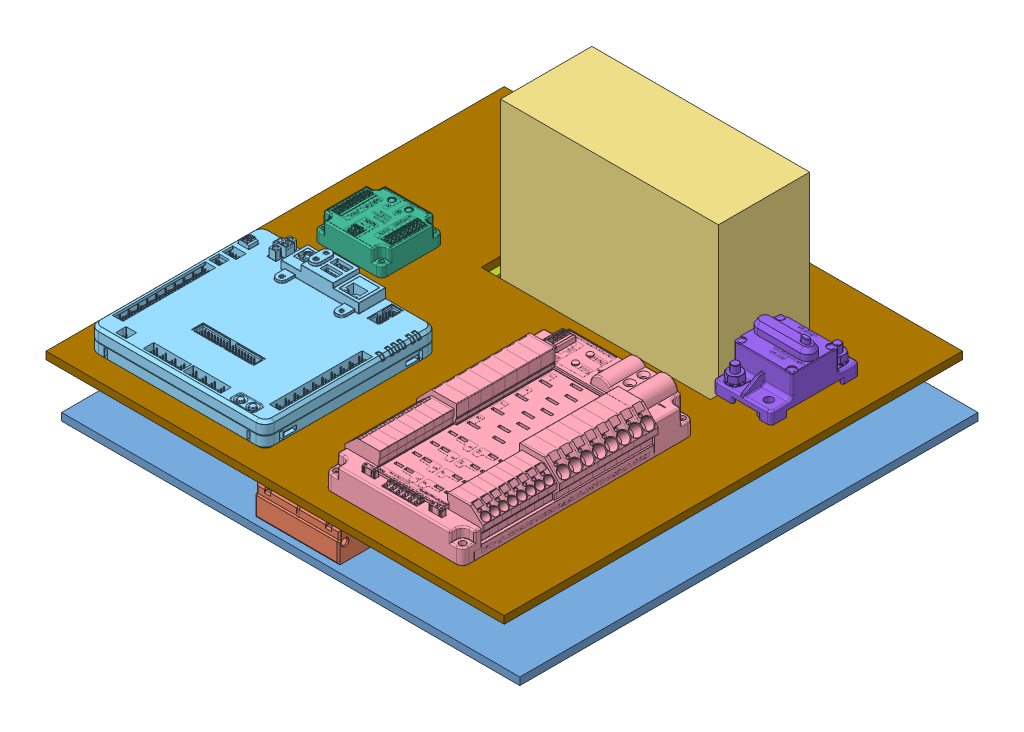
SolidWorks assembly 2board, configuration Default. Lengths in mm.
Overall size (381 173.1 393.95).
14 component instances, 9 part files, 44 mates.
Components (placement in the parent):
- e-board-1: e-board [Default] at (11.1903 208.843 469.4515) size (381 6.22 381)
- Speed Controller-1: Speed Controller [Default] at (218.8091 230.9035 409.6015) x (0 0 -1) z (0 -1 0) size (30.12 70.11 24.39)
- Speed Controller-2: Speed Controller [Default] at (195.4197 230.9035 327.0515) x (0 0 -1) z (0 -1 0) size (30.12 70.11 24.39)
- Speed Controller-3: Speed Controller [Default] at (195.4197 230.9035 288.9515) x (0 0 -1) z (0 -1 0) size (30.12 70.11 24.39)
- Speed Controller-4: Speed Controller [Default] at (195.4197 230.9035 365.1515) x (0 0 -1) z (0 -1 0) size (30.12 70.11 24.39)
- Battery-1: Battery [Default] at (134.8883 215.066 152.2055) x (0 0 1) z (-1 0 0) size (75.95 166.88 181.1)
- PDP-1: PDP [Default] at (283.1225 272.4192 373.3122) x (0 0 1) z (-1 0 0) size (192.68 36.15 120.93)
- Roborio-1: Roborio [Default] at (102.9515 275.391 393.5258) x (1 0 0) z (0 1 0) size (146.27 143.19 36.83)
- VRM-1: VRM [Default] at (71.5666 272.8449 263.7102) size (56.39 19.92 51.56)
- radio b;ock-1: radio b;ock [Default] at (49.2903 215.066 259.9015) size (69.85 25.4 95.25)
- Breaker-1: Breaker [Default] at (342.6603 270.565 198.3394) x (0 0 -1) z (1 0 0) size (73.72 42.2 48.95)
- board with battery cut out-1: board with battery cut out [Default] at (11.1903 259.516 482.4055) size (381 6.22 381)
- Speed Controller-5: Speed Controller [Default] at (201.7697 230.9035 449.4587) x (0 0 -1) z (0 -1 0) size (30.12 70.11 24.39)
- Speed Controller-7: Speed Controller [Default] at (189.0697 230.9035 253.3915) x (0 0 -1) z (0 -1 0) size (30.12 70.11 24.39)
Mates (geometry in assembly coordinates):
- Coincident1: coincident anti-aligned: plane of e-board-1 through (11.1903 215.066 469.4515) normal (0 1 0); plane of Speed Controller-1 through (183.8841 215.066 394.5392) normal (0 -1 0)
- Perpendicular2: perpendicular: plane of e-board-1 through (392.1903 215.066 469.4515) normal (1 0 0); plane of Speed Controller-1 through (231.0297 237.5535 409.3615) normal (0 0 -1)
- Distance1: distance = 57.15 mm: plane of Speed Controller-1 through (231.4297 237.5535 412.3015) normal (0 0 1); line of e-board-1 through (11.1903 208.843 469.4515) axis (1 0 0)
- Distance2: distance = 222.25 mm: line of Speed Controller-1 through (232.2997 237.5535 411.9015) axis (0 0 1); line of e-board-1 through (11.1903 215.066 88.4515) axis (0 0 1)
- Coincident5: coincident anti-aligned: plane of e-board-1 through (11.1903 215.066 469.4515) normal (0 1 0); plane of Speed Controller-4 through (160.4947 215.066 350.0892) normal (0 -1 0)
- Coincident6: coincident anti-aligned: plane of e-board-1 through (11.1903 215.066 469.4515) normal (0 1 0); plane of Speed Controller-3 through (160.4947 215.066 273.8892) normal (0 -1 0)
- Coincident7: coincident anti-aligned: plane of e-board-1 through (11.1903 215.066 469.4515) normal (0 1 0); plane of Speed Controller-2 through (160.4947 215.066 311.9892) normal (0 -1 0)
- Perpendicular3: perpendicular: plane of e-board-1 through (392.1903 215.066 469.4515) normal (1 0 0); plane of Speed Controller-4 through (207.6403 237.5535 364.9115) normal (0 0 -1)
- Perpendicular5: perpendicular: plane of e-board-1 through (392.1903 215.066 469.4515) normal (1 0 0); plane of Speed Controller-3 through (207.6403 237.5535 286.1715) normal (0 0 -1)
- Perpendicular6: perpendicular: plane of e-board-1 through (392.1903 215.066 469.4515) normal (1 0 0); plane of Speed Controller-2 through (207.6403 237.5535 324.2715) normal (0 0 -1)
- Distance3: distance = 184.15 mm: plane of Speed Controller-4 through (208.0403 237.5535 367.4515) normal (1 0 0); line of e-board-1 through (392.1903 215.066 469.4515) axis (0 0 -1)
- Distance5: distance = 184.15 mm aligned: plane of Speed Controller-2 through (208.0403 237.5535 328.0815) normal (1 0 0); plane of e-board-1 through (392.1903 215.066 469.4515) normal (1 0 0)
- Distance6: distance = 101.6 mm aligned: plane of Speed Controller-4 through (209.3103 237.5535 367.8515) normal (0 0 1); plane of e-board-1 through (11.1903 215.066 469.4515) normal (0 0 1)
- Distance7: distance = 139.7 mm aligned: plane of Speed Controller-2 through (208.0403 237.5535 329.7515) normal (0 0 1); plane of e-board-1 through (11.1903 215.066 469.4515) normal (0 0 1)
- Distance8: distance = 184.15 mm: plane of Speed Controller-3 through (208.0403 237.5535 291.2515) normal (1 0 0); line of e-board-1 through (392.1903 215.066 469.4515) axis (0 0 -1)
- Distance9: distance = 177.8 mm aligned: plane of Speed Controller-3 through (208.0403 237.5535 291.6515) normal (0 0 1); plane of e-board-1 through (11.1903 215.066 469.4515) normal (0 0 1)
- Coincident19: coincident anti-aligned: plane of e-board-1 through (11.1903 215.066 469.4515) normal (0 1 0); plane of Battery-1 through (134.8883 215.066 152.2055) normal (0 -1 0)
- Distance11: distance = 76.2 mm aligned: plane of Battery-1 through (315.9903 381.944 152.2055) normal (1 0 0); plane of e-board-1 through (392.1903 215.066 469.4515) normal (1 0 0)
- Coincident39: coincident aligned: plane of e-board-1 through (392.1903 215.066 469.4515) normal (1 0 0); plane of board with battery cut out-1 through (392.1903 272.089 482.4055) normal (1 0 0)
- Distance25: distance = 44.45 mm anti-aligned: plane of e-board-1 through (11.1903 215.066 469.4515) normal (0 1 0); plane of board with battery cut out-1 through (11.1903 259.516 482.4055) normal (0 -1 0)
- Coincident42: coincident anti-aligned: plane of PDP-1 through (225.7185 272.089 465.3364) normal (0 -1 0); plane of board with battery cut out-1 through (11.1903 272.089 482.4055) normal (0 1 0)
- Coincident43: coincident anti-aligned: plane of Breaker-1 through (363.031 272.089 228.8619) normal (0 -1 0); plane of board with battery cut out-1 through (11.1903 272.089 482.4055) normal (0 1 0)
- Coincident45: coincident anti-aligned: plane of VRM-1 through (94.911 272.089 244.163) normal (0 -1 0); plane of board with battery cut out-1 through (11.1903 272.089 482.4055) normal (0 1 0)
- Coincident47: coincident: plane of Roborio-1 through (29.4396 272.089 465.4925) normal (0 1 0); line of board with battery cut out-1 through (11.1903 272.089 482.4055) axis (1 0 0)
- Distance26: distance = 95.25 mm aligned: plane of PDP-1 through (296.9403 288.3814 457.0055) normal (1 0 0); plane of board with battery cut out-1 through (392.1903 265.739 482.4055) normal (1 0 0)
- Distance27: distance = 25.4 mm aligned: plane of PDP-1 through (294.2603 288.3814 457.0055) normal (0 0 1); plane of board with battery cut out-1 through (11.1903 265.739 482.4055) normal (0 0 1)
- Distance28: distance = 25.4 mm aligned: plane of Roborio-1 through (118.1915 285.7584 457.0055) normal (0 0 1); plane of board with battery cut out-1 through (11.1903 265.739 482.4055) normal (0 0 1)
- Distance29: distance = 63.5 mm aligned: plane of Roborio-1 through (74.6903 285.7584 393.5258) normal (-1 0 0); plane of board with battery cut out-1 through (11.1903 265.739 482.4055) normal (-1 0 0)
- Distance30: distance = 38.1 mm: plane of VRM-1 through (49.2903 285.6382 276.5255) normal (-1 0 0); line of board with battery cut out-1 through (11.1903 265.739 101.4055) axis (0 0 1)
- Distance31: distance = 203.2 mm: plane of board with battery cut out-1 through (11.1903 265.739 482.4055) normal (0 0 1); line of VRM-1 through (49.2903 285.6382 279.2055) axis (1 0 0)
- Distance34: distance = 25.4 mm aligned: plane of Breaker-1 through (366.7903 273.105 198.3394) normal (1 0 0); plane of board with battery cut out-1 through (392.1903 265.739 482.4055) normal (1 0 0)
- Distance35: distance = 95.25 mm: plane of Breaker-1 through (357.1383 301.538 196.6555) normal (0 0 -1); line of board with battery cut out-1 through (392.1903 265.739 101.4055) axis (-1 0 0)
- Coincident61: coincident anti-aligned: plane of e-board-1 through (11.1903 215.066 469.4515) normal (0 1 0); plane of Speed Controller-5 through (166.8447 215.066 434.3963) normal (0 -1 0)
- Perpendicular8: perpendicular: line of e-board-1 through (11.1903 215.066 88.4515) axis (0 0 1); plane of Speed Controller-5 through (213.9903 237.5535 447.9487) normal (0 0 -1)
- Distance36: distance = 177.8 mm: plane of Speed Controller-5 through (214.3903 237.5535 451.7587) normal (1 0 0); line of e-board-1 through (392.1903 215.066 469.4515) axis (0 0 -1)
- Distance38: distance = 63.754 mm: line of e-board-1 through (392.1903 215.066 88.4515) axis (-1 0 0); plane of Battery-1 through (134.8883 381.944 152.2055) normal (0 0 -1)
- Coincident75: coincident: plane of Battery-1 through (134.8883 381.944 152.2055) normal (0 0 -1); line of board with battery cut out-1 through (131.8403 272.089 152.2055) axis (1 0 0)
- Coincident76: coincident anti-aligned: plane of e-board-1 through (11.1903 215.066 469.4515) normal (0 1 0); plane of Speed Controller-7 through (154.1447 215.066 238.3292) normal (0 -1 0)
- Perpendicular11: perpendicular: plane of e-board-1 through (392.1903 215.066 469.4515) normal (1 0 0); plane of Speed Controller-7 through (201.2903 237.5535 250.6115) normal (0 0 -1)
- Distance39: distance = 190.5 mm aligned: plane of Speed Controller-7 through (201.6903 237.5535 251.8815) normal (1 0 0); plane of e-board-1 through (392.1903 215.066 469.4515) normal (1 0 0)
- Distance40: distance = 215.9 mm: plane of e-board-1 through (11.1903 215.066 469.4515) normal (0 0 1); point of Speed Controller-7
- Coincident83: coincident: plane of e-board-1 through (11.1903 215.066 469.4515) normal (0 1 0); plane of radio b;ock-1 through (49.2903 215.066 259.9015) normal (0 -1 0)
- Distance41: distance = 76.2 mm: plane of radio b;ock-1 through (49.2903 240.466 164.6515) normal (0 0 -1); plane of e-board-1 through (11.1903 215.066 88.4515) normal (0 0 -1)
- Distance42: distance = 38.1 mm aligned: plane of radio b;ock-1 through (49.2903 240.466 259.9015) normal (-1 0 0); plane of e-board-1 through (11.1903 215.066 469.4515) normal (-1 0 0)
